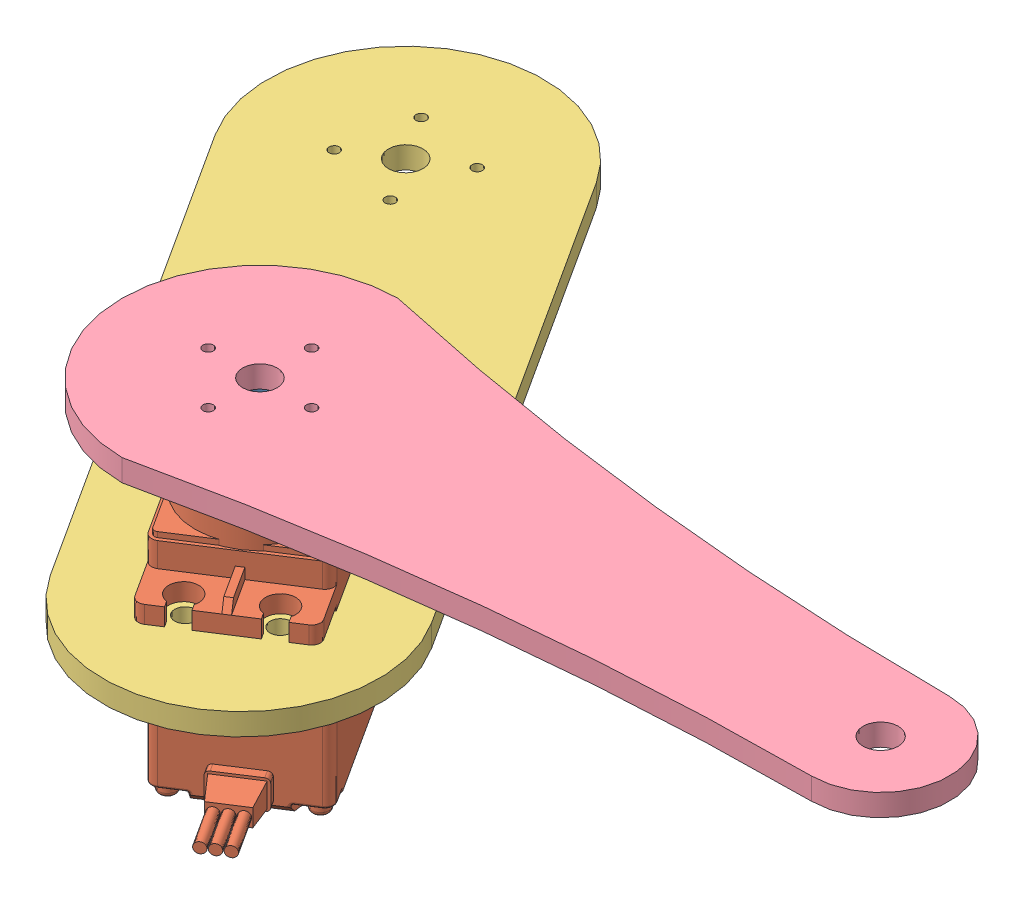
SolidWorks assembly Leg, configuration Défaut. Lengths in mm.
Overall size (165.68 47.79 122.53).
4 component instances, 4 part files, 8 mates.
Components (placement in the parent):
- hs-422_horn_4wings_sws-1: hs-422_horn_4wings_sws [Défaut] at (-9.849 16.7173 0) size (29 5 31)
- moteur-1: moteur [Défaut] at (-23.7487 -4.6733 -3.2787) x (0.840488 0 -0.54183) z (0.54183 0 0.840488) size (19.88 42.12 58.23)
- thigh-1: thigh [Défaut] at (-26.0117 -1.8793 -25.2452) x (0.54183 0 0.840488) z (-0.840488 0 0.54183) size (120 3.17 40)
- tibia-1: tibia [Défaut] at (30.5233 19.2173 0) size (120 3.17 40)
Mates (geometry in assembly coordinates):
- Coaxiale1: concentric anti-aligned: circle of hs-422_horn_4wings_sws-1; circle of tibia-1
- Coïncidente1: coincident anti-aligned: plane of hs-422_horn_4wings_sws-1 through (-9.849 19.2173 0) normal (0 1 0); plane of tibia-1 through (35.151 19.2173 -210) normal (0 -1 0)
- Coaxiale2: concentric aligned: circle of hs-422_horn_4wings_sws-1; circle of tibia-1
- Coaxiale3: concentric anti-aligned: circle of hs-422_horn_4wings_sws-1; circle of moteur-1
- Coïncidente4: coincident anti-aligned: plane of hs-422_horn_4wings_sws-1 through (-21.849 16.7173 0) normal (0 -1 0); plane of moteur-1 through (-7.0969 16.7173 -14.0135) normal (0 1 0)
- Coïncidente8: coincident anti-aligned: plane of moteur-1 through (-23.7487 -4.6733 -3.2787) normal (-0.840488 0 0.54183); plane of thigh-1 through (-12.9451 1.2957 13.4798) normal (0.840488 0 -0.54183)
- Coïncidente9: coincident anti-aligned: plane of moteur-1 through (3.7066 -4.6733 2.745) normal (0.54183 0 0.840488); plane of thigh-1 through (3.8647 1.2957 2.6432) normal (-0.54183 0 -0.840488)
- Coïncidente10: coincident anti-aligned: plane of moteur-1 through (-7.0969 1.2957 -14.0135) normal (0 -1 0); plane of thigh-1 through (-47.8866 1.2957 -59.1776) normal (0 1 0)
